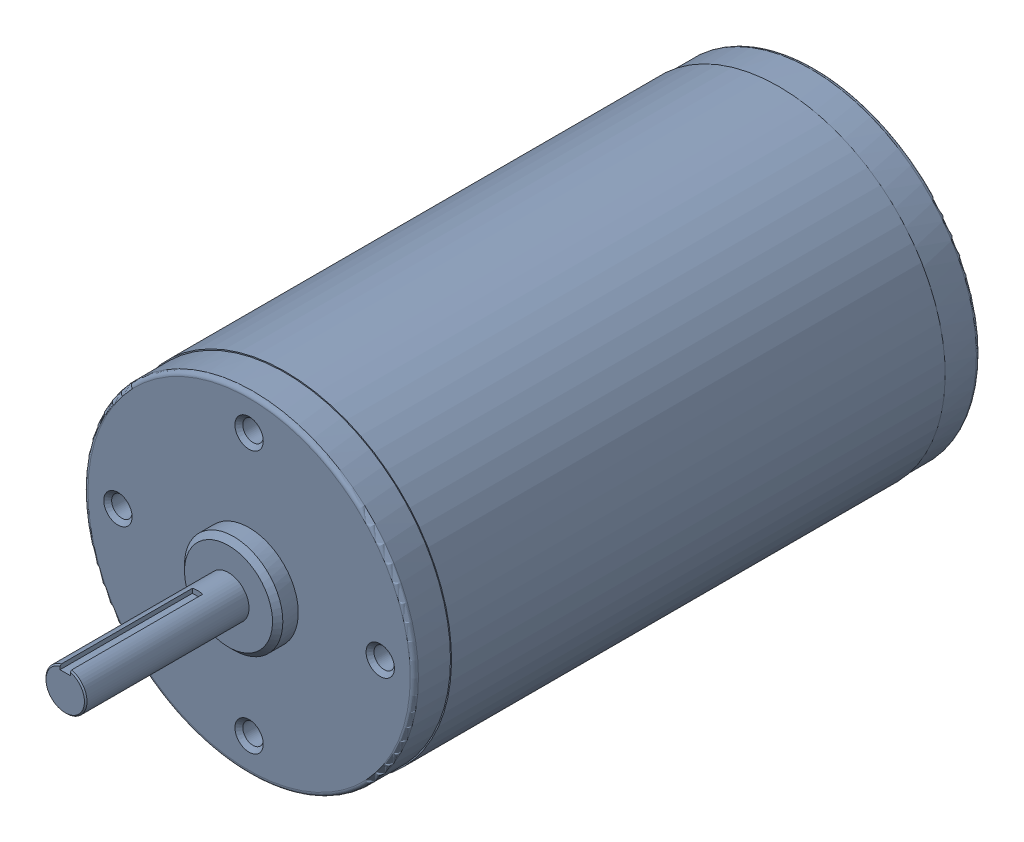
SolidWorks assembly CIM Motor-1, configuration Default. Lengths in mm.
Overall size (64.41 64.41 149.34).
3 component instances, 2 part files, 0 mates.
Components (placement in the parent):
- CIM motor-1-1: CIM motor-1 [Default] at origin size (64.41 64.41 149.34)
- 10-24 UNC x 4_ Phillips Pan Head-1-1: 10-24 UNC x 4_ Phillips Pan Head-1 [Default] at (0 25.4 -98.0336) x (1 0 0) z (0 1 0) size (9.47 105.24 9.47)
- 10-24 UNC x 4_ Phillips Pan Head-1-2: 10-24 UNC x 4_ Phillips Pan Head-1 [Default] at (0 -25.4 -98.0336) x (-1 0 0) z (0 -1 0) size (9.47 105.24 9.47)
